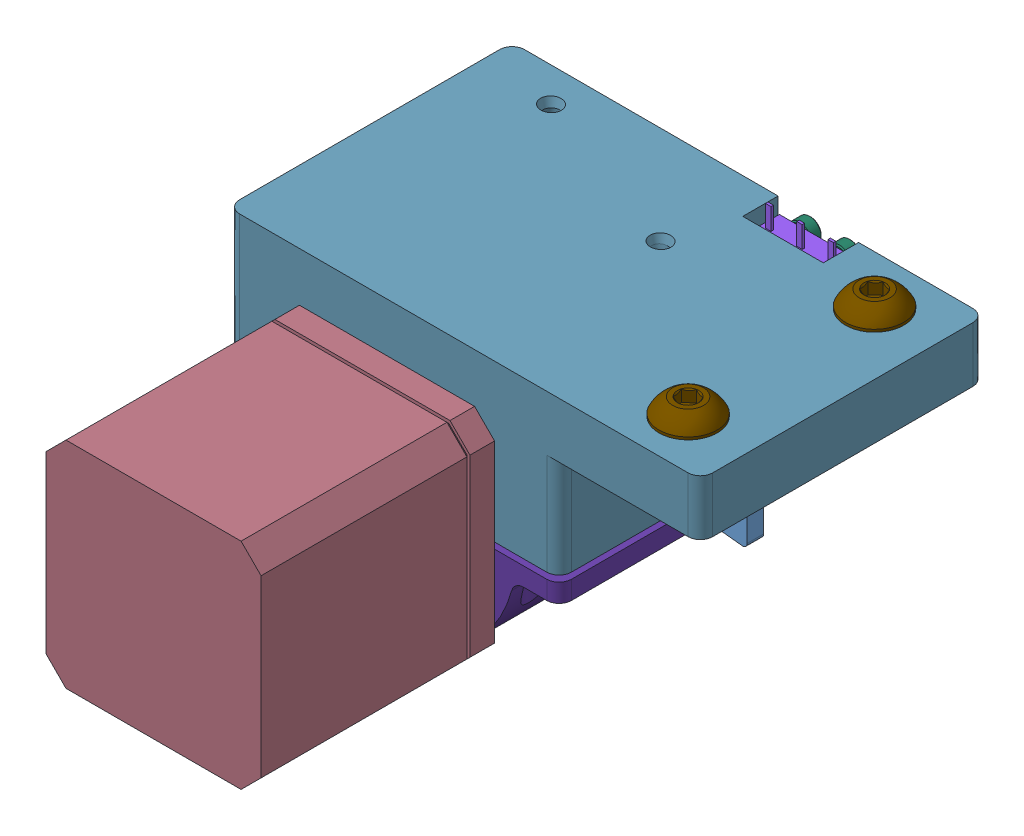
SolidWorks assembly lock_actuator, configuration Default. Lengths in mm.
Overall size (77.07 55.85 86.44).
42 component instances, 18 part files, 0 mates.
Components (placement in the parent):
- spring_pulley-1: spring_pulley [Default] at (-16.518 -37.0987 -50.7165) x (0 1 0) z (-1 0 0) size (52.94 20.78 52.15)
  - fixed_half_pulley_assembly-1: fixed_half_pulley_assembly [Default] at (4.7468 -27.206 -0.7212) size (52.94 18.06 52.15)
    - fixed_half_pulley_with_insert_and_press_fit_parts-1: fixed_half_pulley_with_insert_and_press_fit_parts [Default] at (-8.5074 26.0247 32.0009) x (0.104528 0 0.994522) z (-0.994522 0 0.104528) size (47.36 18.06 48.25)
      - fixed_half_pulley_with_insert-1: fixed_half_pulley_with_insert [Default] at (-30.9364 -26.0247 -11.8058) x (0.104528 0 -0.994522) z (0.994522 0 0.104528) size (44 8 43)
        - half-pulley_Fixed Half-Pulley-1: half-pulley_Fixed Half-Pulley [Default] at (12.3927 18.0247 32.5221) size (44 8 43)
        - m3_heat_set_insert_94180A331_94180A331-1: m3_heat_set_insert_94180A331_94180A331 [Default] at (-7.2105 22.0247 32.5221) x (0 -0.064302 0.99793) z (0 -0.99793 -0.064302) size (5.56 3.88 5.56)
      - m3_16mm_buttohead_screw_92095A184_92095A184-1: m3_16mm_buttohead_screw_92095A184_92095A184 [Default] at (8.4848 1.65 -34.0285) x (0.842903 0 -0.538066) z (0 1 0) size (5.74 5.75 18.06)
      - m3_square_nut-1: m3_square_nut [Default] at (6.681 -5.3 -20.313) x (0.104528 0 -0.994522) z (0 -1 0) size (5.4 2.4 5.4)
    - m3_set_screw_8mm_91390A101_91390A101-1: m3_set_screw_8mm_91390A101_91390A101 [Default] at (12.3927 20.7247 38.8056) x (-0.584342 -0.811508 0) z (0 0 1) size (3.09 3.01 8.09)
  - m3_8mm_buttonhead_screw_92095A181_92095A181-1: m3_8mm_buttonhead_screw_92095A181_92095A181 [Default] at (-5.7011 -5.1813 31.8008) x (0 0.372024 0.928223) z (-1 0 0) size (5.74 5.77 10.05)
  - cinch_plate-1: cinch_plate [Default] at (-3.9644 -15.5813 33.7154) x (0.090348 0 0.99591) z (0.99591 0 -0.090348) size (7 10.08 1.59)
  - cinch_plate-2: cinch_plate [Default] at (-4.0511 -5.1813 31.8008) x (0 0 -1) z (1 0 0) size (7 10.08 1.59)
  - floating_pulley_assembly_with_switch-1: floating_pulley_assembly_with_switch [Default] at (7.573 0.201 -19.0023) x (0.99591 0 -0.090348) z (0.090348 0 0.99591) size (42.72 10.56 43)
    - SS0750300F070P1A-1: SS0750300F070P1A [Default] at (23.1374 -18.5324 48.2097) x (-1 0 0) z (0 0 -1) size (12.7 5.75 10.6)
    - floating_half_pulley_with_insert_and_press_fit_parts-1: floating_half_pulley_with_insert_and_press_fit_parts [Default] at (-14.6658 -20.5824 24.7485) size (42.72 10.4 43)
      - floating_half_pulley_with_insert-1: floating_half_pulley_with_insert [Default] at origin size (42.72 10.4 43)
        - m3_heat_set_insert_94180A331_94180A331-1: m3_heat_set_insert_94180A331_94180A331 [Default] at (0 4.8 26.7112) x (0 -0.064302 0.99793) z (0 -0.99793 -0.064302) size (5.56 3.88 5.56)
        - half-pulley_Floating Half Pulley Underside-1: half-pulley_Floating Half Pulley Underside [Default] at (19.6031 8.8 26.7112) x (1 0 0) z (0 0 -1) size (42.72 10.4 43)
      - 6mm_sleeve_bearing_6658K725_6658K725-1: 6mm_sleeve_bearing_6658K725_6658K725 [Default] at (19.6031 8 26.7112) x (0.690337 0 -0.723488) z (0 -1 0) size (9.02 9.02 6)
    - m2_8mm_buttonhead_screw_91239A705_91239A705-1: m2_8mm_buttonhead_screw_91239A705_91239A705 [Default] at (20.0374 -19.8324 49.7097) x (0.61689 0 -0.787049) z (0 -1 0) size (3.51 3.53 9.63)
    - m2_8mm_buttonhead_screw_91239A705_91239A705-2: m2_8mm_buttonhead_screw_91239A705_91239A705 [Default] at (13.5374 -19.8324 49.7097) x (0.88781 0 0.460209) z (0 -1 0) size (3.51 3.53 9.63)
  - m3_8mm_buttonhead_screw_92095A181_92095A181-2: m3_8mm_buttonhead_screw_92095A181_92095A181 [Default] at (-5.6077 -15.5813 33.8644) x (-0.036839 0.913097 -0.406075) z (-0.99591 0 0.090348) size (5.74 5.77 10.05)
  - m6_shim_0.2mm_thick_98089A247_98089A247-1: m6_shim_0.2mm_thick_98089A247_98089A247 [Default] at (17.1395 -9.3813 31.8008) size (12 0.2 12)
- 14HS13-0804S-PG5-1: 14HS13-0804S-PG5 [Default] at (-48.3189 -19.9592 33.2648) x (-1 0 0) z (0 0 -1) size (35 35 80.2)
- lock_actuator_plates_with_inserts-1: lock_actuator_plates_with_inserts [Default] at (0.6811 4.5408 0) size (77 25.54 46.35)
  - top_lock_actuator_plate_Lock Actuator Base Plate-1: top_lock_actuator_plate_Lock Actuator Base Plate [Default] at (-75 -8 -58.3352) x (0 0 1) z (-1 0 0) size (46.35 25.5 77)
  - m3_heat_set_insert_94180A331_94180A331-1: m3_heat_set_insert_94180A331_94180A331 [Default] at (-70 -24.5 -23.9352) x (-0.819465 0 -0.573129) z (-0.573129 0 0.819465) size (5.56 3.88 5.56)
  - m3_heat_set_insert_94180A331_94180A331-2: m3_heat_set_insert_94180A331_94180A331 [Default] at (-28 -24.5 -9.7352) x (-0.819465 0 -0.573129) z (-0.573129 0 0.819465) size (5.56 3.88 5.56)
  - m3_heat_set_insert_94180A331_94180A331-3: m3_heat_set_insert_94180A331_94180A331 [Default] at (-70 -24.5 -9.7352) x (-0.819465 0 -0.573129) z (-0.573129 0 0.819465) size (5.56 3.88 5.56)
  - m3_heat_set_insert_94180A331_94180A331-4: m3_heat_set_insert_94180A331_94180A331 [Default] at (-28 -24.5 -23.9352) x (-0.819465 0 -0.573129) z (-0.573129 0 0.819465) size (5.56 3.88 5.56)
- SS0750300F070P1A-1: SS0750300F070P1A [Default] at (-30.8189 3.0408 -45.3352) x (1 0 0) z (0 1 0) size (12.7 5.75 10.6)
- m3_8mm_buttonhead_screw_92095A181_92095A181-1: m3_8mm_buttonhead_screw_92095A181_92095A181 [Default] at (-69.3189 -25.6092 -9.7352) x (0.825397 0 0.564552) z (0 -1 0) size (5.74 5.77 10.05)
- m3_8mm_buttonhead_screw_92095A181_92095A181-2: m3_8mm_buttonhead_screw_92095A181_92095A181 [Default] at (-69.3189 -25.6092 -23.9352) x (0.587375 0 0.809315) z (0 -1 0) size (5.74 5.77 10.05)
- m3_8mm_buttonhead_screw_92095A181_92095A181-3: m3_8mm_buttonhead_screw_92095A181_92095A181 [Default] at (-27.3189 -25.6092 -9.7352) x (0.983482 0 -0.181006) z (0 -1 0) size (5.74 5.77 10.05)
- m3_8mm_buttonhead_screw_92095A181_92095A181-4: m3_8mm_buttonhead_screw_92095A181_92095A181 [Default] at (-27.3189 -25.6092 -23.9352) x (0.983482 0 -0.181006) z (0 -1 0) size (5.74 5.77 10.05)
- m2_10mm_socket_head_cap_screw_91292A833_91292A833-1: m2_10mm_socket_head_cap_screw_91292A833_91292A833 [Default] at (-27.7189 1.5408 -41.0852) x (0.917536 -0.397653 0) z (0 0 1) size (3.8 3.8 12.09)
- m2_10mm_socket_head_cap_screw_91292A833_91292A833-2: m2_10mm_socket_head_cap_screw_91292A833_91292A833 [Default] at (-21.2189 1.5408 -41.0852) x (0.968884 -0.247516 0) z (0 0 1) size (3.8 3.8 12.09)
- m5_locking_t_nut_20x20_generic-1: m5_locking_t_nut_20x20_generic [Default] at (-7.3189 -8.4592 -46.0852) size (10 4.5 6)
- m5_locking_t_nut_20x20_generic-2: m5_locking_t_nut_20x20_generic [Default] at (-7.3189 -8.4592 -15.7352) size (10 4.5 6)
- top_lock_actuator_plate_Lock Actuator Motor Clip-1: top_lock_actuator_plate_Lock Actuator Motor Clip [Default] at (-74.3189 -3.4592 -58.3352) x (0 0 1) z (-1 0 0) size (24.2 20 54)
- m5_14mm_buttonhead_screw_92095A211_92095A211-1: m5_14mm_buttonhead_screw_92095A211_92095A211 [Default] at (-7.3189 8.2908 -43.0852) x (-0.311166 0 0.950356) z (0 1 0) size (9.57 9.61 17.42)
- m5_14mm_buttonhead_screw_92095A211_92095A211-2: m5_14mm_buttonhead_screw_92095A211_92095A211 [Default] at (-7.3189 8.2908 -12.7352) x (-0.311166 0 0.950356) z (0 1 0) size (9.57 9.61 17.42)
